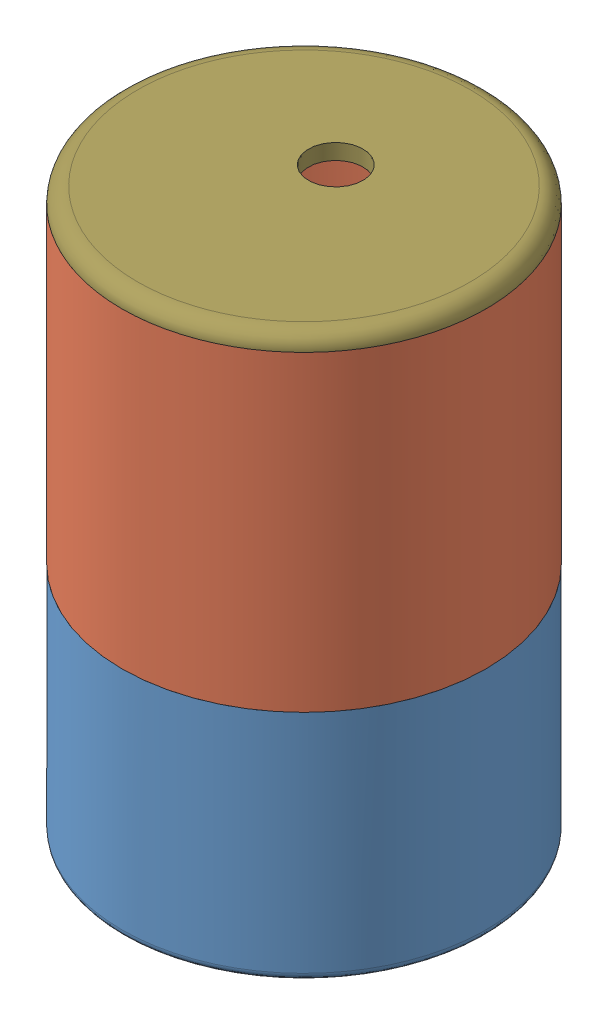
SolidWorks assembly 机器人顶部UWB基站装配V1.1, configuration 默认. Lengths in mm.
Overall size (49.88 72 49.88).
235 component instances, 30 part files, 6 mates.
Components (placement in the parent):
- UWB天线支架-TWR-1: UWB天线支架-TWR [默认] at (-6.8929 -23.6335 62) size (46.7 62 46.7)
- UWB透明保护壳-1: UWB透明保护壳 [默认] at (-6.8929 6.3665 62) size (46.7 42.5 46.7)
- GeekUWB-TWR.step-1: GeekUWB-TWR.step [默认] at (83.3952 -66.0275 64.2043) x (-1 0 0) z (0 0 -1) size (28.7 41.1 6.58)
  - R14.step-1: R14.step [默认] at origin size (0.5 1 0.35)
    - 5863272896.step-1: 5863272896.step [默认] at (77.2159 80.1371 0) x (0 1 0) z (0 0 1) size (1 0.5 0.35)
      - Terminal.step-1: Terminal.step [默认] at (-0.5 -0.25 0) size (0.25 0.5 0.35)
        - Open_CASCADE_STEP_translator_6.8_20.2.1.step-1: Open_CASCADE_STEP_translator_6.8_20.2.1.step [默认] at origin size (0.25 0.5 0.35)
      - Terminal.step-2: Terminal.step [默认] at (0.5 0.25 0) x (-1 0 0) z (0 0 1) size (0.25 0.5 0.35)
        - Open_CASCADE_STEP_translator_6.8_20.2.1.step-1: Open_CASCADE_STEP_translator_6.8_20.2.1.step [默认] at origin size (0.25 0.5 0.35)
      - Mid_Body.step-1: Mid_Body.step [默认] at (-0.5 -0.25 0) size (0.93 0.5 0.28)
      - Mark.step-1: Mark.step [默认] at (-0.25 -0.25 0.315) size (0.5 0.5 0.03)
  - C7.step-1: C7.step [默认] at origin size (1 0.5 0.5)
    - 5863272512.step-1: 5863272512.step [默认] at (78.8669 91.4399 0) x (-1 0 0) z (0 0 1) size (1 0.5 0.5)
      - Terminal-1.step-1: Terminal-1.step [默认] at (-0.5 -0.25 0) size (1 0.5 0.5)
        - Open_CASCADE_STEP_translator_6.8_54.1.1.step-1: Open_CASCADE_STEP_translator_6.8_54.1.1.step [默认] at origin size (0.25 0.5 0.5)
        - Open_CASCADE_STEP_translator_6.8_54.1.2.step-1: Open_CASCADE_STEP_translator_6.8_54.1.2.step [默认] at origin size (0.25 0.5 0.5)
      - Mid_Body-0.step-1: Mid_Body-0.step [默认] at (-0.5 -0.25 0) size (0.5 0.5 0.5)
        - Open_CASCADE_STEP_translator_6.8_54.2.1.step-1: Open_CASCADE_STEP_translator_6.8_54.2.1.step [默认] at origin size (0.5 0.5 0.5)
  - Y1.step-1: Y1.step [默认] at origin size (1.31 3.21 0.71)
    - 123123123.step-1: 123123123.step [默认] at (79.121 88.3921 0) x (0 1 0) z (0 0 1) size (3.21 1.31 0.71)
  - R7.step-1: R7.step [默认] at origin size (1 0.5 0.35)
    - 5863271360.step-1: 5863271360.step [默认] at (88.0109 97.2819 0) x (-1 0 0) z (0 0 1) size (1 0.5 0.35)
      - Terminal-2.step-1: Terminal-2.step [默认] at (-0.5 -0.25 0) size (0.25 0.5 0.35)
        - Open_CASCADE_STEP_translator_6.8_20.2.1-1.step-1: Open_CASCADE_STEP_translator_6.8_20.2.1-1.step [默认] at origin size (0.25 0.5 0.35)
      - Terminal-2.step-2: Terminal-2.step [默认] at (0.5 0.25 0) x (-1 0 0) z (0 0 1) size (0.25 0.5 0.35)
        - Open_CASCADE_STEP_translator_6.8_20.2.1-1.step-1: Open_CASCADE_STEP_translator_6.8_20.2.1-1.step [默认] at origin size (0.25 0.5 0.35)
      - Mid_Body-2.step-1: Mid_Body-2.step [默认] at (-0.5 -0.25 0) size (0.93 0.5 0.28)
      - Mark-3.step-1: Mark-3.step [默认] at (-0.25 -0.25 0.315) size (0.5 0.5 0.03)
  - R10.step-1: R10.step [默认] at origin size (1 0.5 0.35)
    - 5863271744.step-1: 5863271744.step [默认] at (101.3461 99.0601 0) x (1 0 0) z (0 0 1) size (1 0.5 0.35)
      - Terminal-3.step-1: Terminal-3.step [默认] at (-0.5 -0.25 0) size (0.25 0.5 0.35)
        - Open_CASCADE_STEP_translator_6.8_20.2.1-4.step-1: Open_CASCADE_STEP_translator_6.8_20.2.1-4.step [默认] at origin size (0.25 0.5 0.35)
      - Terminal-3.step-2: Terminal-3.step [默认] at (0.5 0.25 0) x (-1 0 0) z (0 0 1) size (0.25 0.5 0.35)
        - Open_CASCADE_STEP_translator_6.8_20.2.1-4.step-1: Open_CASCADE_STEP_translator_6.8_20.2.1-4.step [默认] at origin size (0.25 0.5 0.35)
      - Mid_Body-5.step-1: Mid_Body-5.step [默认] at (-0.5 -0.25 0) size (0.93 0.5 0.28)
      - Mark-6.step-1: Mark-6.step [默认] at (-0.25 -0.25 0.315) size (0.5 0.5 0.03)
  - R9.step-1: R9.step [默认] at origin size (1 0.5 0.35)
    - 5863271744.step-1: 5863271744.step [默认] at (101.3461 100.2031 0) x (1 0 0) z (0 0 1) size (1 0.5 0.35)
      - Terminal-3.step-1: Terminal-3.step [默认] at (-0.5 -0.25 0) size (0.25 0.5 0.35)
        - Open_CASCADE_STEP_translator_6.8_20.2.1-4.step-1: Open_CASCADE_STEP_translator_6.8_20.2.1-4.step [默认] at origin size (0.25 0.5 0.35)
      - Terminal-3.step-2: Terminal-3.step [默认] at (0.5 0.25 0) x (-1 0 0) z (0 0 1) size (0.25 0.5 0.35)
        - Open_CASCADE_STEP_translator_6.8_20.2.1-4.step-1: Open_CASCADE_STEP_translator_6.8_20.2.1-4.step [默认] at origin size (0.25 0.5 0.35)
      - Mid_Body-5.step-1: Mid_Body-5.step [默认] at (-0.5 -0.25 0) size (0.93 0.5 0.28)
      - Mark-6.step-1: Mark-6.step [默认] at (-0.25 -0.25 0.315) size (0.5 0.5 0.03)
  - R8.step-1: R8.step [默认] at origin size (1 0.5 0.35)
    - 5863271360.step-1: 5863271360.step [默认] at (82.0419 87.8839 0) x (-1 0 0) z (0 0 1) size (1 0.5 0.35)
      - Terminal-2.step-1: Terminal-2.step [默认] at (-0.5 -0.25 0) size (0.25 0.5 0.35)
        - Open_CASCADE_STEP_translator_6.8_20.2.1-1.step-1: Open_CASCADE_STEP_translator_6.8_20.2.1-1.step [默认] at origin size (0.25 0.5 0.35)
      - Terminal-2.step-2: Terminal-2.step [默认] at (0.5 0.25 0) x (-1 0 0) z (0 0 1) size (0.25 0.5 0.35)
        - Open_CASCADE_STEP_translator_6.8_20.2.1-1.step-1: Open_CASCADE_STEP_translator_6.8_20.2.1-1.step [默认] at origin size (0.25 0.5 0.35)
      - Mid_Body-2.step-1: Mid_Body-2.step [默认] at (-0.5 -0.25 0) size (0.93 0.5 0.28)
      - Mark-3.step-1: Mark-3.step [默认] at (-0.25 -0.25 0.315) size (0.5 0.5 0.03)
  - R6.step-1: R6.step [默认] at origin size (1 0.5 0.35)
    - 5863271744.step-1: 5863271744.step [默认] at (100.7111 89.2811 0) x (1 0 0) z (0 0 1) size (1 0.5 0.35)
      - Terminal-3.step-1: Terminal-3.step [默认] at (-0.5 -0.25 0) size (0.25 0.5 0.35)
        - Open_CASCADE_STEP_translator_6.8_20.2.1-4.step-1: Open_CASCADE_STEP_translator_6.8_20.2.1-4.step [默认] at origin size (0.25 0.5 0.35)
      - Terminal-3.step-2: Terminal-3.step [默认] at (0.5 0.25 0) x (-1 0 0) z (0 0 1) size (0.25 0.5 0.35)
        - Open_CASCADE_STEP_translator_6.8_20.2.1-4.step-1: Open_CASCADE_STEP_translator_6.8_20.2.1-4.step [默认] at origin size (0.25 0.5 0.35)
      - Mid_Body-5.step-1: Mid_Body-5.step [默认] at (-0.5 -0.25 0) size (0.93 0.5 0.28)
      - Mark-6.step-1: Mark-6.step [默认] at (-0.25 -0.25 0.315) size (0.5 0.5 0.03)
  - R5.step-1: R5.step [默认] at origin size (1 0.5 0.35)
    - 5863271744.step-1: 5863271744.step [默认] at (101.3461 101.3461 0) x (1 0 0) z (0 0 1) size (1 0.5 0.35)
      - Terminal-3.step-1: Terminal-3.step [默认] at (-0.5 -0.25 0) size (0.25 0.5 0.35)
        - Open_CASCADE_STEP_translator_6.8_20.2.1-4.step-1: Open_CASCADE_STEP_translator_6.8_20.2.1-4.step [默认] at origin size (0.25 0.5 0.35)
      - Terminal-3.step-2: Terminal-3.step [默认] at (0.5 0.25 0) x (-1 0 0) z (0 0 1) size (0.25 0.5 0.35)
        - Open_CASCADE_STEP_translator_6.8_20.2.1-4.step-1: Open_CASCADE_STEP_translator_6.8_20.2.1-4.step [默认] at origin size (0.25 0.5 0.35)
      - Mid_Body-5.step-1: Mid_Body-5.step [默认] at (-0.5 -0.25 0) size (0.93 0.5 0.28)
      - Mark-6.step-1: Mark-6.step [默认] at (-0.25 -0.25 0.315) size (0.5 0.5 0.03)
  - R2.step-1: R2.step [默认] at origin size (1 0.5 0.35)
    - 5863271744.step-1: 5863271744.step [默认] at (80.8991 85.4711 0) x (1 0 0) z (0 0 1) size (1 0.5 0.35)
      - Terminal-3.step-1: Terminal-3.step [默认] at (-0.5 -0.25 0) size (0.25 0.5 0.35)
        - Open_CASCADE_STEP_translator_6.8_20.2.1-4.step-1: Open_CASCADE_STEP_translator_6.8_20.2.1-4.step [默认] at origin size (0.25 0.5 0.35)
      - Terminal-3.step-2: Terminal-3.step [默认] at (0.5 0.25 0) x (-1 0 0) z (0 0 1) size (0.25 0.5 0.35)
        - Open_CASCADE_STEP_translator_6.8_20.2.1-4.step-1: Open_CASCADE_STEP_translator_6.8_20.2.1-4.step [默认] at origin size (0.25 0.5 0.35)
      - Mid_Body-5.step-1: Mid_Body-5.step [默认] at (-0.5 -0.25 0) size (0.93 0.5 0.28)
      - Mark-6.step-1: Mark-6.step [默认] at (-0.25 -0.25 0.315) size (0.5 0.5 0.03)
  - R3.step-1: R3.step [默认] at origin size (1 0.5 0.35)
    - 5863271744.step-1: 5863271744.step [默认] at (80.8991 84.4551 0) x (1 0 0) z (0 0 1) size (1 0.5 0.35)
      - Terminal-3.step-1: Terminal-3.step [默认] at (-0.5 -0.25 0) size (0.25 0.5 0.35)
        - Open_CASCADE_STEP_translator_6.8_20.2.1-4.step-1: Open_CASCADE_STEP_translator_6.8_20.2.1-4.step [默认] at origin size (0.25 0.5 0.35)
      - Terminal-3.step-2: Terminal-3.step [默认] at (0.5 0.25 0) x (-1 0 0) z (0 0 1) size (0.25 0.5 0.35)
        - Open_CASCADE_STEP_translator_6.8_20.2.1-4.step-1: Open_CASCADE_STEP_translator_6.8_20.2.1-4.step [默认] at origin size (0.25 0.5 0.35)
      - Mid_Body-5.step-1: Mid_Body-5.step [默认] at (-0.5 -0.25 0) size (0.93 0.5 0.28)
      - Mark-6.step-1: Mark-6.step [默认] at (-0.25 -0.25 0.315) size (0.5 0.5 0.03)
  - R1.step-1: R1.step [默认] at origin size (0.5 1 0.35)
    - 5863272896.step-1: 5863272896.step [默认] at (78.294 80.1531 0) x (0 1 0) z (0 0 1) size (1 0.5 0.35)
      - Terminal.step-1: Terminal.step [默认] at (-0.5 -0.25 0) size (0.25 0.5 0.35)
        - Open_CASCADE_STEP_translator_6.8_20.2.1.step-1: Open_CASCADE_STEP_translator_6.8_20.2.1.step [默认] at origin size (0.25 0.5 0.35)
      - Terminal.step-2: Terminal.step [默认] at (0.5 0.25 0) x (-1 0 0) z (0 0 1) size (0.25 0.5 0.35)
        - Open_CASCADE_STEP_translator_6.8_20.2.1.step-1: Open_CASCADE_STEP_translator_6.8_20.2.1.step [默认] at origin size (0.25 0.5 0.35)
      - Mid_Body.step-1: Mid_Body.step [默认] at (-0.5 -0.25 0) size (0.93 0.5 0.28)
      - Mark.step-1: Mark.step [默认] at (-0.25 -0.25 0.315) size (0.5 0.5 0.03)
  - R4.step-1: R4.step [默认] at origin size (1 0.5 0.35)
    - 5863271744.step-1: 5863271744.step [默认] at (80.8991 83.4391 0) x (1 0 0) z (0 0 1) size (1 0.5 0.35)
      - Terminal-3.step-1: Terminal-3.step [默认] at (-0.5 -0.25 0) size (0.25 0.5 0.35)
        - Open_CASCADE_STEP_translator_6.8_20.2.1-4.step-1: Open_CASCADE_STEP_translator_6.8_20.2.1-4.step [默认] at origin size (0.25 0.5 0.35)
      - Terminal-3.step-2: Terminal-3.step [默认] at (0.5 0.25 0) x (-1 0 0) z (0 0 1) size (0.25 0.5 0.35)
        - Open_CASCADE_STEP_translator_6.8_20.2.1-4.step-1: Open_CASCADE_STEP_translator_6.8_20.2.1-4.step [默认] at origin size (0.25 0.5 0.35)
      - Mid_Body-5.step-1: Mid_Body-5.step [默认] at (-0.5 -0.25 0) size (0.93 0.5 0.28)
      - Mark-6.step-1: Mark-6.step [默认] at (-0.25 -0.25 0.315) size (0.5 0.5 0.03)
  - R13.step-1: R13.step [默认] at origin size (1 0.5 0.35)
    - 5863271360.step-1: 5863271360.step [默认] at (98.8059 91.4399 0) x (-1 0 0) z (0 0 1) size (1 0.5 0.35)
      - Terminal-2.step-1: Terminal-2.step [默认] at (-0.5 -0.25 0) size (0.25 0.5 0.35)
        - Open_CASCADE_STEP_translator_6.8_20.2.1-1.step-1: Open_CASCADE_STEP_translator_6.8_20.2.1-1.step [默认] at origin size (0.25 0.5 0.35)
      - Terminal-2.step-2: Terminal-2.step [默认] at (0.5 0.25 0) x (-1 0 0) z (0 0 1) size (0.25 0.5 0.35)
        - Open_CASCADE_STEP_translator_6.8_20.2.1-1.step-1: Open_CASCADE_STEP_translator_6.8_20.2.1-1.step [默认] at origin size (0.25 0.5 0.35)
      - Mid_Body-2.step-1: Mid_Body-2.step [默认] at (-0.5 -0.25 0) size (0.93 0.5 0.28)
      - Mark-3.step-1: Mark-3.step [默认] at (-0.25 -0.25 0.315) size (0.5 0.5 0.03)
  - R12.step-1: R12.step [默认] at origin size (0.5 1 0.35)
    - 5863271552.step-1: 5863271552.step [默认] at (101.2191 86.7769 0) x (0 -1 0) z (0 0 1) size (1 0.5 0.35)
      - Terminal-4.step-1: Terminal-4.step [默认] at (-0.5 -0.25 0) size (0.25 0.5 0.35)
        - Open_CASCADE_STEP_translator_6.8_20.2.1-7.step-1: Open_CASCADE_STEP_translator_6.8_20.2.1-7.step [默认] at origin size (0.25 0.5 0.35)
      - Terminal-4.step-2: Terminal-4.step [默认] at (0.5 0.25 0) x (-1 0 0) z (0 0 1) size (0.25 0.5 0.35)
        - Open_CASCADE_STEP_translator_6.8_20.2.1-7.step-1: Open_CASCADE_STEP_translator_6.8_20.2.1-7.step [默认] at origin size (0.25 0.5 0.35)
      - Mid_Body-8.step-1: Mid_Body-8.step [默认] at (-0.5 -0.25 0) size (0.93 0.5 0.28)
      - Mark-9.step-1: Mark-9.step [默认] at (-0.25 -0.25 0.315) size (0.5 0.5 0.03)
  - R11.step-1: R11.step [默认] at origin size (1 0.5 0.35)
    - 5863271744.step-1: 5863271744.step [默认] at (90.9941 97.3479 0) x (1 0 0) z (0 0 1) size (1 0.5 0.35)
      - Terminal-3.step-1: Terminal-3.step [默认] at (-0.5 -0.25 0) size (0.25 0.5 0.35)
        - Open_CASCADE_STEP_translator_6.8_20.2.1-4.step-1: Open_CASCADE_STEP_translator_6.8_20.2.1-4.step [默认] at origin size (0.25 0.5 0.35)
      - Terminal-3.step-2: Terminal-3.step [默认] at (0.5 0.25 0) x (-1 0 0) z (0 0 1) size (0.25 0.5 0.35)
        - Open_CASCADE_STEP_translator_6.8_20.2.1-4.step-1: Open_CASCADE_STEP_translator_6.8_20.2.1-4.step [默认] at origin size (0.25 0.5 0.35)
      - Mid_Body-5.step-1: Mid_Body-5.step [默认] at (-0.5 -0.25 0) size (0.93 0.5 0.28)
      - Mark-6.step-1: Mark-6.step [默认] at (-0.25 -0.25 0.315) size (0.5 0.5 0.03)
  - D4.step-1: D4.step [默认] at origin size (1.01 0.5 0.45)
    - User_Library-led_0402LED0402_red_.step-1: User_Library-led_0402LED0402_red_.step [默认] at (98.6791 89.281 0) x (1 0 0) z (0 0 1) size (1.01 0.5 0.45)
  - D1.step-1: D1.step [默认] at origin size (1.01 0.5 0.45)
    - User_Library-led_0402LED0402_red_.step-1: User_Library-led_0402LED0402_red_.step [默认] at (99.3141 100.203 0) x (1 0 0) z (0 0 1) size (1.01 0.5 0.45)
  - D2.step-1: D2.step [默认] at origin size (1.01 0.5 0.45)
    - User_Library-led_0402LED0402_red_.step-1: User_Library-led_0402LED0402_red_.step [默认] at (99.3141 99.06 0) x (1 0 0) z (0 0 1) size (1.01 0.5 0.45)
  - D3.step-1: D3.step [默认] at origin size (1.01 0.5 0.45)
    - User_Library-led_0402LED0402_red_.step-1: User_Library-led_0402LED0402_red_.step [默认] at (99.3141 101.346 0) x (1 0 0) z (0 0 1) size (1.01 0.5 0.45)
  - C5.step-1: C5.step [默认] at origin size (0.5 1 0.5)
    - 5863270784.step-1: 5863270784.step [默认] at (98.6791 96.5199 0) x (0 -1 0) z (0 0 1) size (1 0.5 0.5)
      - Terminal-5.step-1: Terminal-5.step [默认] at (-0.5 -0.25 0) size (1 0.5 0.5)
        - Open_CASCADE_STEP_translator_6.8_54.1.1-10.step-1: Open_CASCADE_STEP_translator_6.8_54.1.1-10.step [默认] at origin size (0.25 0.5 0.5)
        - Open_CASCADE_STEP_translator_6.8_54.1.2-11.step-1: Open_CASCADE_STEP_translator_6.8_54.1.2-11.step [默认] at origin size (0.25 0.5 0.5)
      - Mid_Body-1.step-1: Mid_Body-1.step [默认] at (-0.5 -0.25 0) size (0.5 0.5 0.5)
        - Open_CASCADE_STEP_translator_6.8_54.2.1-12.step-1: Open_CASCADE_STEP_translator_6.8_54.2.1-12.step [默认] at origin size (0.5 0.5 0.5)
  - C6.step-1: C6.step [默认] at origin size (1 0.5 0.5)
    - 5863272512.step-1: 5863272512.step [默认] at (82.0419 88.9126 0) x (-1 0 0) z (0 0 1) size (1 0.5 0.5)
      - Terminal-1.step-1: Terminal-1.step [默认] at (-0.5 -0.25 0) size (1 0.5 0.5)
        - Open_CASCADE_STEP_translator_6.8_54.1.1.step-1: Open_CASCADE_STEP_translator_6.8_54.1.1.step [默认] at origin size (0.25 0.5 0.5)
        - Open_CASCADE_STEP_translator_6.8_54.1.2.step-1: Open_CASCADE_STEP_translator_6.8_54.1.2.step [默认] at origin size (0.25 0.5 0.5)
      - Mid_Body-0.step-1: Mid_Body-0.step [默认] at (-0.5 -0.25 0) size (0.5 0.5 0.5)
        - Open_CASCADE_STEP_translator_6.8_54.2.1.step-1: Open_CASCADE_STEP_translator_6.8_54.2.1.step [默认] at origin size (0.5 0.5 0.5)
  - C4.step-1: C4.step [默认] at origin size (1.6 0.81 0.81)
    - C0603_3D.step-1: C0603_3D.step [默认] at (100.7109 96.3929 0) x (-1 0 0) z (0 0 1) size (1.6 0.81 0.81)
  - C3.step-1: C3.step [默认] at origin size (0.5 1 0.5)
    - 5863270784.step-1: 5863270784.step [默认] at (100.0761 86.7849 0) x (0 -1 0) z (0 0 1) size (1 0.5 0.5)
      - Terminal-5.step-1: Terminal-5.step [默认] at (-0.5 -0.25 0) size (1 0.5 0.5)
        - Open_CASCADE_STEP_translator_6.8_54.1.1-10.step-1: Open_CASCADE_STEP_translator_6.8_54.1.1-10.step [默认] at origin size (0.25 0.5 0.5)
        - Open_CASCADE_STEP_translator_6.8_54.1.2-11.step-1: Open_CASCADE_STEP_translator_6.8_54.1.2-11.step [默认] at origin size (0.25 0.5 0.5)
      - Mid_Body-1.step-1: Mid_Body-1.step [默认] at (-0.5 -0.25 0) size (0.5 0.5 0.5)
        - Open_CASCADE_STEP_translator_6.8_54.2.1-12.step-1: Open_CASCADE_STEP_translator_6.8_54.2.1-12.step [默认] at origin size (0.5 0.5 0.5)
  - C2.step-1: C2.step [默认] at origin size (0.81 1.6 0.81)
    - C0603_3D.step-1: C0603_3D.step [默认] at (98.5521 86.9949 0) x (0 -1 0) z (0 0 1) size (1.6 0.81 0.81)
  - C1.step-1: C1.step [默认] at origin size (1.6 0.81 0.81)
    - C0603_3D.step-1: C0603_3D.step [默认] at (78.9939 92.8369 0) x (-1 0 0) z (0 0 1) size (1.6 0.81 0.81)
  - USB.step-1: USB.step [默认] at origin size (8.96 7.76 4.27)
    - 1.step-1: 1.step [默认] at (98.1049 122.7063 3.5) x (1 0 0) z (0 0 -1) size (8.96 7.76 4.27)
  - U3.step-1: U3.step [默认] at origin size (13.2 23 2.9)
    - DWM1000_Module.step-1: DWM1000_Module.step [默认] at (90.301 102.0509 -0.4115) x (-1 0 0) z (0 -1 0) size (13.2 2.9 23)
  - U2.step-1: U2.step [默认] at origin size (2.9 2.8 1.2)
    - PCB1.step-1: PCB1.step [默认] at (80.4724 95.505 0) x (0 1 0) z (0 0 1) size (2.8 2.9 1.2)
  - U1.step-1: U1.step [默认] at origin size (12.01 12.01 1.45)
    - LQFP64-10x10.step-1: LQFP64-10x10.step [默认] at (90.2971 89.5349 0) x (0 -1 0) z (0 0 1) size (12.01 12.01 1.45)
      - LQFP64-10X10_1_AF0_ASM.step-1: LQFP64-10X10_1_AF0_ASM.step [默认] at origin size (12.01 12.01 1.45)
        - _0_25_100.step-1: _0_25_100.step [默认] at (-5 2.75 0.75) x (0 1 0) z (0 0 1) size (0.25 1 0.8)
        - _0_25_100.step-2: _0_25_100.step [默认] at (5 -1.25 0.75) x (0 -1 0) z (0 0 1) size (0.25 1 0.8)
        - _0_25_100.step-3: _0_25_100.step [默认] at (-0.75 5 0.75) size (0.25 1 0.8)
        - _0_25_100.step-4: _0_25_100.step [默认] at (-5 -2.75 0.75) x (0 1 0) z (0 0 1) size (0.25 1 0.8)
        - _0_25_100.step-5: _0_25_100.step [默认] at (-2.75 -5 0.75) x (-1 0 0) z (0 0 1) size (0.25 1 0.8)
        - _0_25_100.step-6: _0_25_100.step [默认] at (2.75 -5 0.75) x (-1 0 0) z (0 0 1) size (0.25 1 0.8)
        - _0_25_100.step-7: _0_25_100.step [默认] at (-5 3.75 0.75) x (0 1 0) z (0 0 1) size (0.25 1 0.8)
        - _0_25_100.step-8: _0_25_100.step [默认] at (5 -2.25 0.75) x (0 -1 0) z (0 0 1) size (0.25 1 0.8)
        - _0_25_100.step-9: _0_25_100.step [默认] at (0.25 5 0.75) size (0.25 1 0.8)
        - _0_25_100.step-10: _0_25_100.step [默认] at (-5 -1.75 0.75) x (0 1 0) z (0 0 1) size (0.25 1 0.8)
        - _0_25_100.step-11: _0_25_100.step [默认] at (5 3.25 0.75) x (0 -1 0) z (0 0 1) size (0.25 1 0.8)
        - _0_25_100.step-12: _0_25_100.step [默认] at (-0.25 -5 0.75) x (-1 0 0) z (0 0 1) size (0.25 1 0.8)
        - _0_25_100.step-13: _0_25_100.step [默认] at (5 -3.25 0.75) x (0 -1 0) z (0 0 1) size (0.25 1 0.8)
        - _0_25_100.step-14: _0_25_100.step [默认] at (1.25 5 0.75) size (0.25 1 0.8)
        - _0_25_100.step-15: _0_25_100.step [默认] at (-5 -0.75 0.75) x (0 1 0) z (0 0 1) size (0.25 1 0.8)
        - _0_25_100.step-16: _0_25_100.step [默认] at (5 2.25 0.75) x (0 -1 0) z (0 0 1) size (0.25 1 0.8)
        - _0_25_100.step-17: _0_25_100.step [默认] at (-3.25 -5 0.75) x (-1 0 0) z (0 0 1) size (0.25 1 0.8)
        - _0_25_100.step-18: _0_25_100.step [默认] at (2.25 -5 0.75) x (-1 0 0) z (0 0 1) size (0.25 1 0.8)
        - _0_25_100.step-19: _0_25_100.step [默认] at (2.25 5 0.75) size (0.25 1 0.8)
        - _0_25_100.step-20: _0_25_100.step [默认] at (-5 0.25 0.75) x (0 1 0) z (0 0 1) size (0.25 1 0.8)
        - _0_25_100.step-21: _0_25_100.step [默认] at (5 1.25 0.75) x (0 -1 0) z (0 0 1) size (0.25 1 0.8)
        - _0_25_100.step-22: _0_25_100.step [默认] at (-3.25 5 0.75) size (0.25 1 0.8)
        - _0_25_100.step-23: _0_25_100.step [默认] at (-0.75 -5 0.75) x (-1 0 0) z (0 0 1) size (0.25 1 0.8)
        - _0_25_100.step-24: _0_25_100.step [默认] at (3.25 5 0.75) size (0.25 1 0.8)
        - _0_25_100.step-25: _0_25_100.step [默认] at (-5 1.25 0.75) x (0 1 0) z (0 0 1) size (0.25 1 0.8)
        - _0_25_100.step-26: _0_25_100.step [默认] at (5 0.25 0.75) x (0 -1 0) z (0 0 1) size (0.25 1 0.8)
        - _0_25_100.step-27: _0_25_100.step [默认] at (-2.25 5 0.75) size (0.25 1 0.8)
        - _0_25_100.step-28: _0_25_100.step [默认] at (-3.75 -5 0.75) x (-1 0 0) z (0 0 1) size (0.25 1 0.8)
        - _0_25_100.step-29: _0_25_100.step [默认] at (1.75 -5 0.75) x (-1 0 0) z (0 0 1) size (0.25 1 0.8)
        - _0_25_100.step-30: _0_25_100.step [默认] at (-5 2.25 0.75) x (0 1 0) z (0 0 1) size (0.25 1 0.8)
        - _0_25_100.step-31: _0_25_100.step [默认] at (5 -0.75 0.75) x (0 -1 0) z (0 0 1) size (0.25 1 0.8)
        - _0_25_100.step-32: _0_25_100.step [默认] at (-1.25 5 0.75) size (0.25 1 0.8)
        - _0_25_100.step-33: _0_25_100.step [默认] at (-5 -3.25 0.75) x (0 1 0) z (0 0 1) size (0.25 1 0.8)
        - _0_25_100.step-34: _0_25_100.step [默认] at (-1.25 -5 0.75) x (-1 0 0) z (0 0 1) size (0.25 1 0.8)
        - LQFP64_10X10___A.step-1: LQFP64_10X10___A.step [默认] at origin size (10 10 1.4)
        - _0_25_100.step-35: _0_25_100.step [默认] at (-5 3.25 0.75) x (0 1 0) z (0 0 1) size (0.25 1 0.8)
        - _0_25_100.step-36: _0_25_100.step [默认] at (5 -1.75 0.75) x (0 -1 0) z (0 0 1) size (0.25 1 0.8)
        - _0_25_100.step-37: _0_25_100.step [默认] at (-0.25 5 0.75) size (0.25 1 0.8)
        - _0_25_100.step-38: _0_25_100.step [默认] at (-5 -2.25 0.75) x (0 1 0) z (0 0 1) size (0.25 1 0.8)
        - _0_25_100.step-39: _0_25_100.step [默认] at (5 3.75 0.75) x (0 -1 0) z (0 0 1) size (0.25 1 0.8)
        - _0_25_100.step-40: _0_25_100.step [默认] at (1.25 -5 0.75) x (-1 0 0) z (0 0 1) size (0.25 1 0.8)
        - _0_25_100.step-41: _0_25_100.step [默认] at (5 -2.75 0.75) x (0 -1 0) z (0 0 1) size (0.25 1 0.8)
        - _0_25_100.step-42: _0_25_100.step [默认] at (0.75 5 0.75) size (0.25 1 0.8)
        - _0_25_100.step-43: _0_25_100.step [默认] at (-5 -1.25 0.75) x (0 1 0) z (0 0 1) size (0.25 1 0.8)
        - _0_25_100.step-44: _0_25_100.step [默认] at (5 2.75 0.75) x (0 -1 0) z (0 0 1) size (0.25 1 0.8)
        - _0_25_100.step-45: _0_25_100.step [默认] at (-1.75 -5 0.75) x (-1 0 0) z (0 0 1) size (0.25 1 0.8)
        - _0_25_100.step-46: _0_25_100.step [默认] at (3.75 -5 0.75) x (-1 0 0) z (0 0 1) size (0.25 1 0.8)
        - _0_25_100.step-47: _0_25_100.step [默认] at (5 -3.75 0.75) x (0 -1 0) z (0 0 1) size (0.25 1 0.8)
        - _0_25_100.step-48: _0_25_100.step [默认] at (1.75 5 0.75) size (0.25 1 0.8)
        - _0_25_100.step-49: _0_25_100.step [默认] at (-5 -0.25 0.75) x (0 1 0) z (0 0 1) size (0.25 1 0.8)
        - _0_25_100.step-50: _0_25_100.step [默认] at (5 1.75 0.75) x (0 -1 0) z (0 0 1) size (0.25 1 0.8)
        - _0_25_100.step-51: _0_25_100.step [默认] at (-3.75 5 0.75) size (0.25 1 0.8)
        - _0_25_100.step-52: _0_25_100.step [默认] at (0.75 -5 0.75) x (-1 0 0) z (0 0 1) size (0.25 1 0.8)
        - _0_25_100.step-53: _0_25_100.step [默认] at (2.75 5 0.75) size (0.25 1 0.8)
        - _0_25_100.step-54: _0_25_100.step [默认] at (-5 0.75 0.75) x (0 1 0) z (0 0 1) size (0.25 1 0.8)
        - _0_25_100.step-55: _0_25_100.step [默认] at (5 0.75 0.75) x (0 -1 0) z (0 0 1) size (0.25 1 0.8)
        - _0_25_100.step-56: _0_25_100.step [默认] at (-2.75 5 0.75) size (0.25 1 0.8)
        - _0_25_100.step-57: _0_25_100.step [默认] at (-2.25 -5 0.75) x (-1 0 0) z (0 0 1) size (0.25 1 0.8)
        - _0_25_100.step-58: _0_25_100.step [默认] at (3.25 -5 0.75) x (-1 0 0) z (0 0 1) size (0.25 1 0.8)
        - _0_25_100.step-59: _0_25_100.step [默认] at (3.75 5 0.75) size (0.25 1 0.8)
        - _0_25_100.step-60: _0_25_100.step [默认] at (-5 1.75 0.75) x (0 1 0) z (0 0 1) size (0.25 1 0.8)
        - _0_25_100.step-61: _0_25_100.step [默认] at (5 -0.25 0.75) x (0 -1 0) z (0 0 1) size (0.25 1 0.8)
        - _0_25_100.step-62: _0_25_100.step [默认] at (-1.75 5 0.75) size (0.25 1 0.8)
        - _0_25_100.step-63: _0_25_100.step [默认] at (-5 -3.75 0.75) x (0 1 0) z (0 0 1) size (0.25 1 0.8)
        - _0_25_100.step-64: _0_25_100.step [默认] at (0.25 -5 0.75) x (-1 0 0) z (0 0 1) size (0.25 1 0.8)
  - Board.step-1: Board.step [默认] at origin size (28.7 31.37 0.41)
- UWB盖板-1: UWB盖板 [默认] at (-6.8929 48.3665 62) x (0.997501 0 -0.070651) z (0.070651 0 0.997501) size (46.7 5 46.7)
Mates (geometry in assembly coordinates):
- 同心1: concentric anti-aligned: cylinder of UWB天线支架-TWR-1 through (-6.8929 6.3665 62) axis (0 -1 0) radius 21.35; cylinder of UWB透明保护壳-1 through (-6.8929 3.8665 62) axis (0 1 0) radius 21.35
- 重合1: coincident anti-aligned: plane of UWB天线支架-TWR-1 through (-21.235 38.3665 64.6158) normal (0 0 -1); plane of GeekUWB-TWR.step-1/Board.step-1 through (5.0002 7.0355 64.6158) normal (0 0 1)
- 同心2: concentric anti-aligned: cylinder of UWB天线支架-TWR-1 through (5.0362 35.8265 124.6158) axis (0 0 -1) radius 1.0654; cylinder of GeekUWB-TWR.step-1/Board.step-1 through (5.0362 35.8265 64.6158) axis (0 0 1) radius 1.0875
- 重合2: coincident aligned: plane of UWB天线支架-TWR-1 through (-6.8929 38.3665 62) normal (0 1 0); plane of GeekUWB-TWR.step-1/Board.step-1 through (4.5282 38.3665 64.6158) normal (0 1 0)
- 重合3: coincident anti-aligned: plane of UWB天线支架-TWR-1 through (-6.8929 6.3665 62) normal (0 1 0); plane of UWB透明保护壳-1 through (-6.8929 6.3665 62) normal (0 -1 0)
- 重合4: coincident anti-aligned: plane of UWB透明保护壳-1 through (-6.8929 46.3665 62) normal (0 1 0); plane of UWB盖板-1 through (-6.8929 46.3665 62) normal (0 -1 0)
